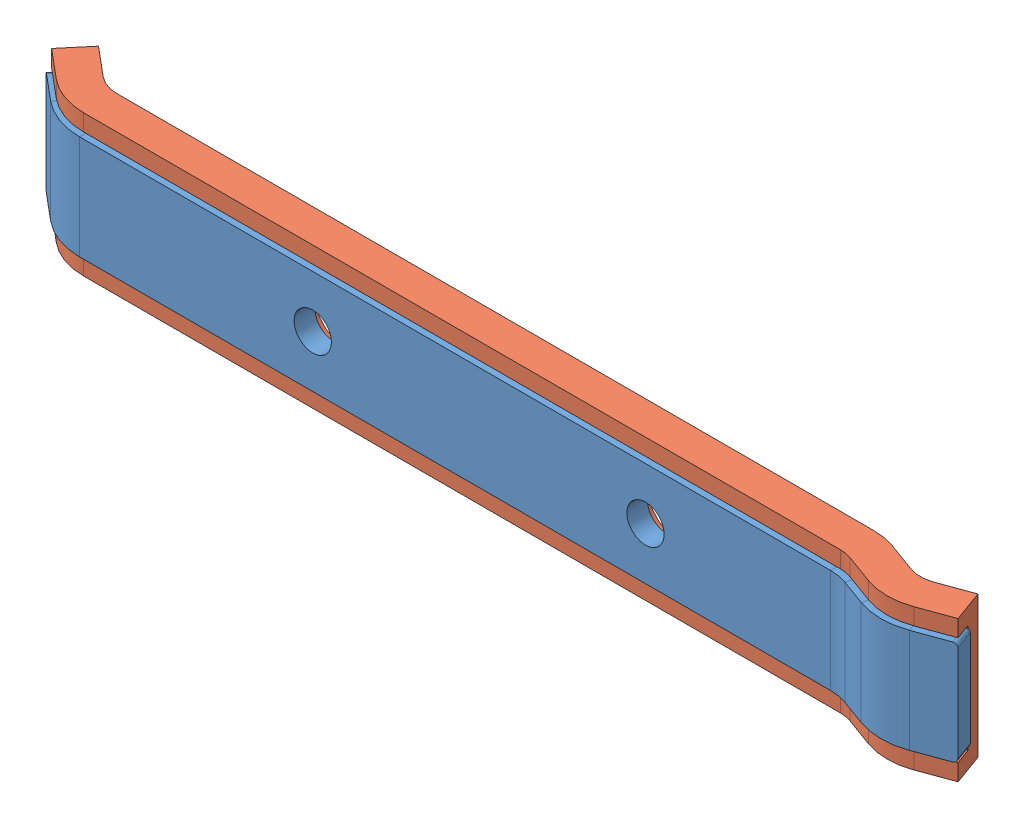
SolidWorks assembly 6340213, configuration Default. Lengths in mm.
Overall size (228.94 34 20.67).
2 component instances, 2 part files, 3 mates.
Components (placement in the parent):
- 6340214-2: 6340214 [Default] at origin size (228.94 25 17.65)
- 20866-1: 20866 [Opbukket for 6340213] x (-1 0 0) z (0 1 0) size (227.69 19.66 34)
Mates (geometry in assembly coordinates):
- Concentric1: concentric aligned: cylinder of 6340214-2 through (155 12.5 5) axis (0 0 -1) radius 4.5; cylinder of 20866-1 through (155 12.5 8.1671) axis (0 0 -1) radius 9
- Concentric2: concentric aligned: cylinder of 6340214-2 through (75 12.5 5) axis (0 0 -1) radius 4.5; cylinder of 20866-1 through (75 12.5 8.1671) axis (0 0 -1) radius 9
- Coincident1: coincident anti-aligned: plane of 6340214-2 through (1 1 0) normal (0 0 -1); plane of 20866-1 through (58.4648 25.5 0) normal (0 0 1)
